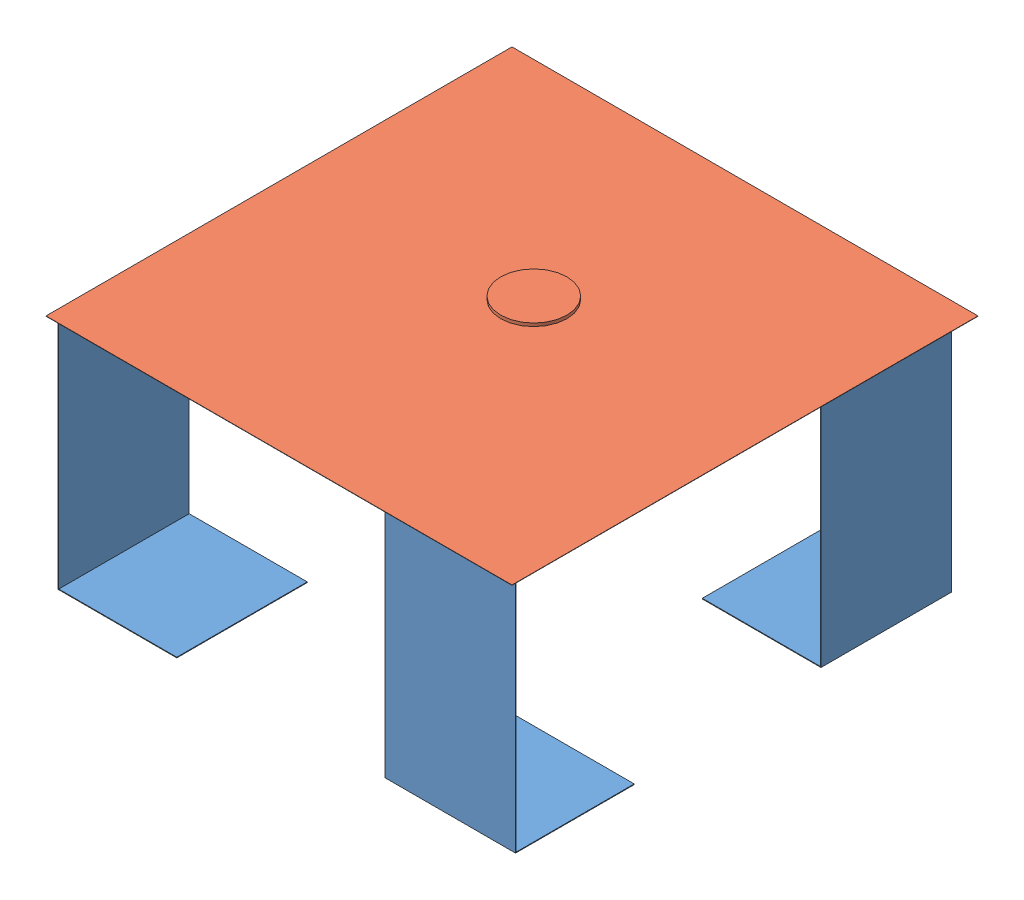
SolidWorks assembly Plataforma, configuration Default. Lengths in mm.
Overall size (1500 772.89 1500).
5 component instances, 2 part files, 0 mates.
Components (placement in the parent):
- Célula-1: Célula [Default] at (24.6591 -51.886 -1477.4858) size (420 762 382)
- Célula-2: Célula [Default] at (19 -51.886 -19.9596) x (0 0 -1) z (1 0 0) size (420 762 382)
- Célula-3: Célula [Default] at (1464.549 -51.886 -1450.0012) x (0 0 1) z (-1 0 0) size (420 762 382)
- Célula-4: Célula [Default] at (1490.4664 -51.886 -20.9958) x (-1 0 0) z (0 0 -1) size (420 762 382)
- Superfície-1: Superfície [Default] at (0 710 0) size (1500 11 1500)
